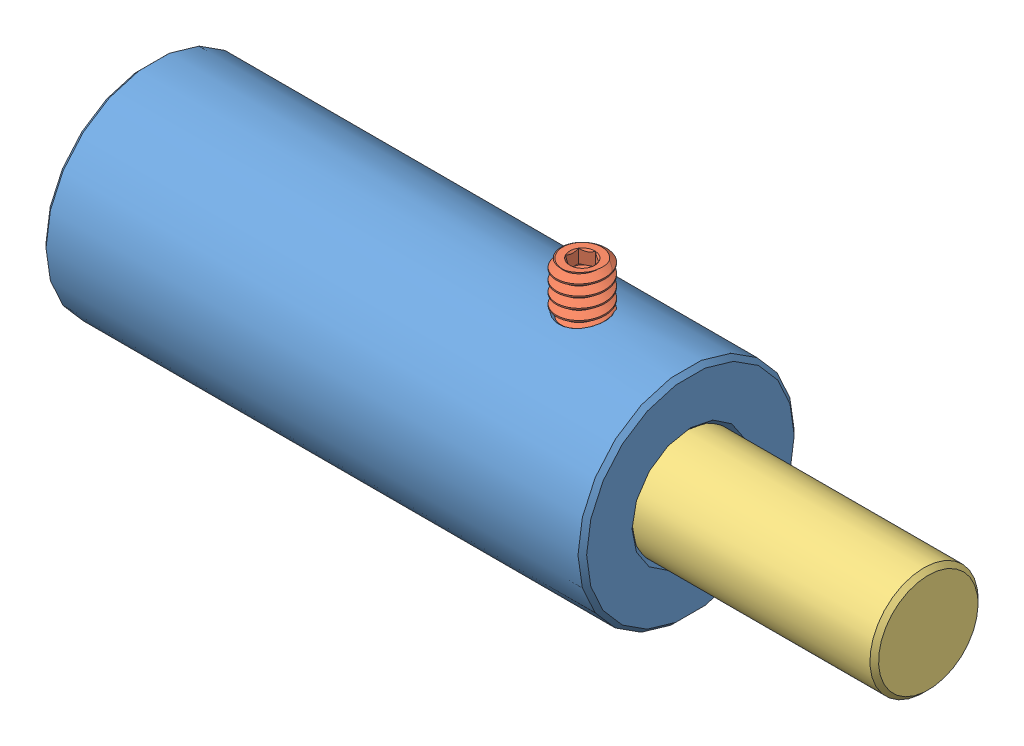
SolidWorks assembly A_SetScrew, configuration Default. Lengths in mm.
Overall size (45.72 15.5 12.7).
3 component instances, 3 part files, 3 mates.
Components (placement in the parent):
- FemaleRodforSetScrew-1: FemaleRodforSetScrew [Default] at (-9.2984 20.5291 31.1647) size (31.75 12.7 12.7)
- 4-40 Set Screw-1: 4-40 Set Screw [90778A111] at (16.1016 26.241 31.1647) x (0.998567 0 0.053509) z (0 1 0) size (3.28 2.92 6.61)
- MaleRodforSetScrew-1: MaleRodforSetScrew [Default] at (11.0216 20.5291 31.1647) x (1 0 0) z (0 -0.06911 0.997609) size (25.4 6.35 6.35)
Mates (geometry in assembly coordinates):
- Concentric1: concentric: cylinder of FemaleRodforSetScrew-1 through (22.4516 20.5291 31.1647) axis (-1 0 0) radius 6.35; cylinder of MaleRodforSetScrew-1 through (48.0144 20.5291 31.1647) axis (-1 0 0) radius 3.175
- Concentric2: concentric aligned: cylinder of FemaleRodforSetScrew-1 through (16.1016 37.0391 31.1647) axis (0 -1 0) radius 1.1303; cone of 4-40 Set Screw-1 through (16.1016 28.6223 31.1647) axis (0 -1 0)
- Distance1: distance = 11.43 mm anti-aligned: plane of FemaleRodforSetScrew-1 through (22.4516 20.5291 31.1647) normal (1 0 0); plane of MaleRodforSetScrew-1 through (11.0216 20.5291 31.1647) normal (-1 0 0)
